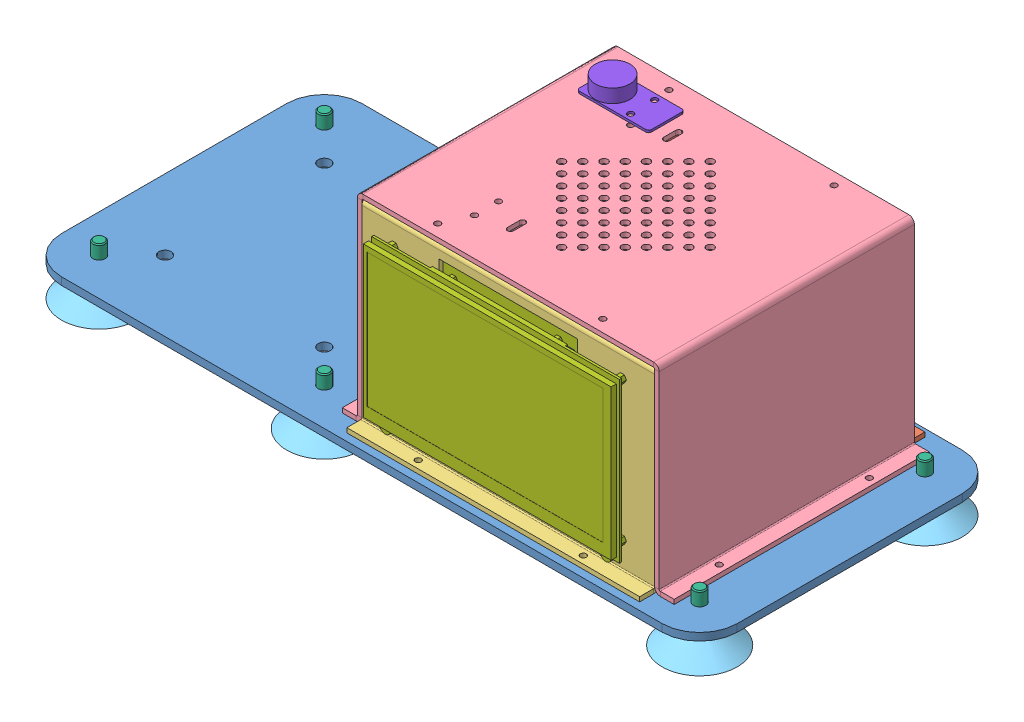
SolidWorks assembly 树莓派底座, configuration 默认. Lengths in mm.
Overall size (461.89 173.5 214.03).
24 component instances, 8 part files, 27 mates.
Components (placement in the parent):
- 底座-1: 底座 [默认] at origin size (450 35 200)
- 长边外壳2-1: 长边外壳2 [默认] at (82.5 65 -82) x (-1 0 0) z (0 1 0) size (195 23 130)
- 长边外壳1-1: 长边外壳1 [默认] at (82.5 65 85) x (1 0 0) z (0 -1 0) size (195 23 130)
- 顶盖-1: 顶盖 [默认] at (82.5 133 0) size (221 133 170)
- 底座吸盘-1: 底座吸盘 [默认] at (-200 -14 75) x (0.97823 0 -0.207524) z (0.207524 0 0.97823) size (50 34 50)
  - 底座吸盘-1: 底座吸盘 [默认] at origin size (50 20 50)
  - hexagon socket countersunk head screws gb-2: hexagon socket countersunk head screws gb [GB_FASTENER_SCREWS_HSCHS M8X20-N] at (0 3 0) x (0 1 0) z (-0.546944 0 0.837169) size (20 15.24 15.24)
- 底座吸盘-2: 底座吸盘 [默认] at (-200 -14 -75) x (0.965229 0 0.261404) z (-0.261404 0 0.965229) size (50 34 50)
  - 底座吸盘-1: 底座吸盘 [默认] at origin size (50 20 50)
  - hexagon socket countersunk head screws gb-2: hexagon socket countersunk head screws gb [GB_FASTENER_SCREWS_HSCHS M8X20-N] at (0 3 0) x (0 1 0) z (-0.546944 0 0.837169) size (20 15.24 15.24)
- 底座吸盘-3: 底座吸盘 [默认] at (-50 -14 -75) x (0.994322 0 -0.106417) z (0.106417 0 0.994322) size (50 34 50)
  - 底座吸盘-1: 底座吸盘 [默认] at origin size (50 20 50)
  - hexagon socket countersunk head screws gb-2: hexagon socket countersunk head screws gb [GB_FASTENER_SCREWS_HSCHS M8X20-N] at (0 3 0) x (0 1 0) z (-0.546944 0 0.837169) size (20 15.24 15.24)
- 底座吸盘-4: 底座吸盘 [默认] at (-50 -14 75) x (0.919595 0 0.392869) z (-0.392869 0 0.919595) size (50 34 50)
  - 底座吸盘-1: 底座吸盘 [默认] at origin size (50 20 50)
  - hexagon socket countersunk head screws gb-2: hexagon socket countersunk head screws gb [GB_FASTENER_SCREWS_HSCHS M8X20-N] at (0 3 0) x (0 1 0) z (-0.546944 0 0.837169) size (20 15.24 15.24)
- 底座吸盘-5: 底座吸盘 [默认] at (200 -14 -75) x (0.95624 0 -0.292584) z (0.292584 0 0.95624) size (50 34 50)
  - 底座吸盘-1: 底座吸盘 [默认] at origin size (50 20 50)
  - hexagon socket countersunk head screws gb-2: hexagon socket countersunk head screws gb [GB_FASTENER_SCREWS_HSCHS M8X20-N] at (0 3 0) x (0 1 0) z (-0.546944 0 0.837169) size (20 15.24 15.24)
- 底座吸盘-6: 底座吸盘 [默认] at (200 -14 75) x (0.984809 0 -0.17364) z (0.17364 0 0.984809) size (50 34 50)
  - 底座吸盘-1: 底座吸盘 [默认] at origin size (50 20 50)
  - hexagon socket countersunk head screws gb-2: hexagon socket countersunk head screws gb [GB_FASTENER_SCREWS_HSCHS M8X20-N] at (0 3 0) x (0 1 0) z (-0.546944 0 0.837169) size (20 15.24 15.24)
- 显示屏-1: 显示屏 [默认] at (82.5 68.5 95.5) x (-1 0 0) z (0 1 0) size (165 17 109.5)
- 语音合成模块-1: 语音合成模块 [默认] at (27 138 -52) size (48 10.5 24)
Mates (geometry in assembly coordinates):
- 重合10: coincident anti-aligned: plane of 底座-1 through (0 0 0) normal (0 1 0); plane of 长边外壳1-1 through (82.5 0 85) normal (0 -1 0)
- 同心7: concentric aligned: circle of 底座-1; circle of 长边外壳1-1
- 同心8: concentric aligned: circle of 底座-1; circle of 长边外壳1-1
- 重合13: coincident anti-aligned: plane of 底座-1 through (0 0 0) normal (0 1 0); plane of 长边外壳2-1 through (82.5 0 -82) normal (0 -1 0)
- 同心11: concentric aligned: circle of 底座-1; circle of 长边外壳2-1
- 同心12: concentric aligned: circle of 底座-1; circle of 长边外壳2-1
- 重合20: coincident anti-aligned: plane of 长边外壳1-1 through (82.5 130 85) normal (0 1 0); plane of 顶盖-1 through (82.5 130 0) normal (0 -1 0)
- 同心13: concentric aligned: circle of 长边外壳1-1; circle of 顶盖-1
- 同心14: concentric aligned: circle of 长边外壳1-1; circle of 顶盖-1
- 重合211: coincident anti-aligned: plane of 底座吸盘-4/底座吸盘-1 through (-50 -5 75) normal (0 1 0); plane of 底座-1 through (0 -5 0) normal (0 -1 0)
- 同心15: concentric anti-aligned: circle of 底座-1; circle of 底座吸盘-4/底座吸盘-1
- 同心16: concentric anti-aligned: circle of 底座-1; circle of 底座吸盘-1/底座吸盘-1
- 同心17: concentric aligned: circle of 底座-1; circle of 底座吸盘-2/底座吸盘-1
- 同心18: concentric aligned: circle of 底座-1; circle of 底座吸盘-3/底座吸盘-1
- 同心19: concentric aligned: circle of 底座-1; circle of 底座吸盘-5/底座吸盘-1
- 同心20: concentric aligned: circle of 底座-1; circle of 底座吸盘-6/底座吸盘-1
- 重合22: coincident anti-aligned: plane of 底座-1 through (0 -5 0) normal (0 -1 0); plane of 底座吸盘-6/底座吸盘-1 through (200 -5 75) normal (0 1 0)
- 重合23: coincident anti-aligned: plane of 底座-1 through (0 -5 0) normal (0 -1 0); plane of 底座吸盘-5/底座吸盘-1 through (200 -5 -75) normal (0 1 0)
- 重合24: coincident anti-aligned: plane of 底座-1 through (0 -5 0) normal (0 -1 0); plane of 底座吸盘-3/底座吸盘-1 through (-50 -5 -75) normal (0 1 0)
- 重合25: coincident anti-aligned: plane of 底座-1 through (0 -5 0) normal (0 -1 0); plane of 底座吸盘-2/底座吸盘-1 through (-200 -5 -75) normal (0 1 0)
- 重合26: coincident anti-aligned: plane of 底座-1 through (0 -5 0) normal (0 -1 0); plane of 底座吸盘-1/底座吸盘-1 through (-200 -5 75) normal (0 1 0)
- 同心21: concentric anti-aligned: circle of 长边外壳1-1; circle of 显示屏-1
- 重合212: coincident anti-aligned: plane of 长边外壳1-1 through (82.5 65 85) normal (0 0 1); plane of 显示屏-1 through (82.5 68.5 85) normal (0 0 -1)
- 同心24: concentric anti-aligned: circle of 长边外壳1-1; circle of 显示屏-1
- 距离1: distance = 5 mm anti-aligned: plane of 语音合成模块-1 through (27 138 -52) normal (0 -1 0); plane of 顶盖-1 through (82.5 133 0) normal (0 1 0)
- 同心25: concentric aligned: circle of 顶盖-1; circle of 语音合成模块-1
- 同心26: concentric aligned: circle of 顶盖-1; circle of 语音合成模块-1
